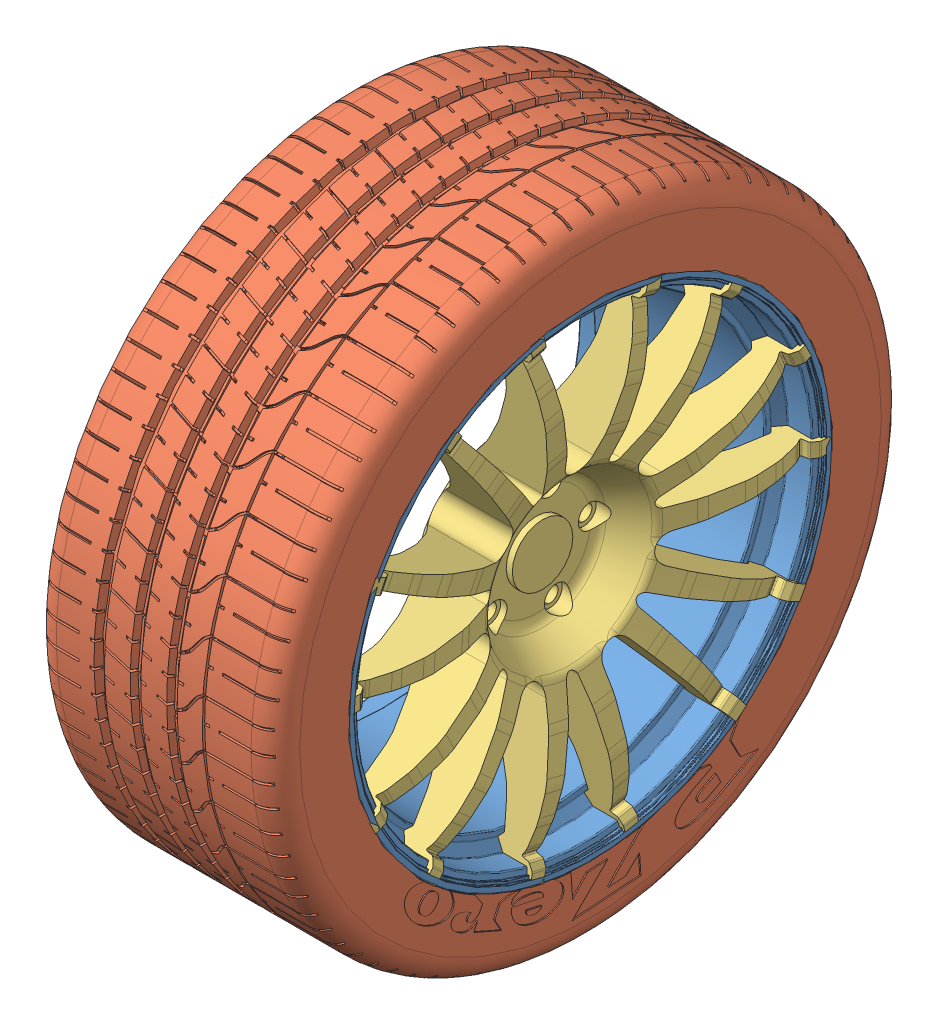
SolidWorks assembly Wheel, configuration rearwheel. Lengths in mm.
Overall size (359.09 1296.77 1296.74).
3 component instances, 3 part files, 4 mates.
Components (placement in the parent):
- Rim-1: Rim [rear] at origin size (357.1 707.14 707.14)
- Tread-1: Tread [rear] at (-254.8405 -409.9654 200.2059) x (1 0 0) z (0 -0.788276 -0.615322) size (354.98 923.8 923.96)
- Spokes-1: Spokes [rear] at (32.1617 -191.3563 246.1539) x (1 0 0) z (0 -0.96911 0.246629) size (133.93 693.41 707.21)
Mates (geometry in assembly coordinates):
- Concentric1: concentric aligned: cylinder of Rim-1 through (-232.6932 -254 0) axis (-1 0 0) radius 309.1677; cylinder of Tread-1 through (-304.7004 -254 0) axis (-1 0 0) radius 353.568
- Coincident1: coincident aligned: plane of Rim-1 through (50.2818 97.8002 0) normal (1 0 0); plane of Tread-1 through (50.2818 -471.5582 278.7091) normal (1 0 0)
- Concentric3: concentric aligned: cylinder of Rim-1 through (-232.6932 -254 0) axis (-1 0 0) radius 309.1677; cylinder of Spokes-1 through (-19.7881 -254 0) axis (-1 0 0) radius 44.196
- Coincident3: coincident anti-aligned: plane of Rim-1 through (46.7462 90.0217 0) normal (1 0 0); plane of Spokes-1 through (46.7462 -166.9744 341.961) normal (-1 0 0)
